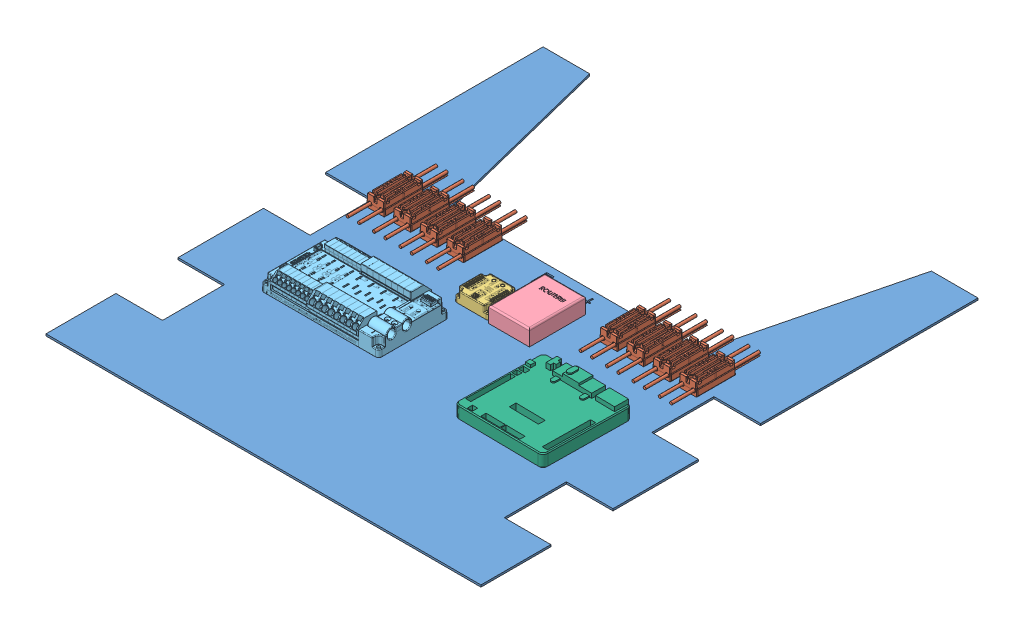
SolidWorks assembly 2017 electronics plate, configuration Default. Lengths in mm.
Overall size (711.2 41.27 812.8).
13 component instances, 6 part files, 6 mates.
Components (placement in the parent):
- electronics plate-1: electronics plate [Default] at origin size (711.2 3.17 812.8)
- Victor-SP-Motor-controller-20217-9090-1: Victor-SP-Motor-controller-20217-9090 [Default] at (-258.5801 9.1448 -219.6738) size (30.24 20.93 144.78)
- Victor-SP-Motor-controller-20217-9090-3: Victor-SP-Motor-controller-20217-9090 [Default] at (-215.4001 9.1448 -219.6738) size (30.24 20.93 144.78)
- Victor-SP-Motor-controller-20217-9090-4: Victor-SP-Motor-controller-20217-9090 [Default] at (-172.2201 9.1448 -219.6738) size (30.24 20.93 144.78)
- Victor-SP-Motor-controller-20217-9090-5: Victor-SP-Motor-controller-20217-9090 [Default] at (-129.0401 9.1448 -219.6738) size (30.24 20.93 144.78)
- VoltReg-217-4245-1: VoltReg-217-4245 [Default] at (-39.4381 10.281 -153.6848) size (56.39 19.92 51.56)
- RouterCrude-1: RouterCrude [Default] at (37.6355 15.875 -155.8516) size (66.67 25.4 92.08)
- PowerDistribution-1: PowerDistribution [Default] at (-149.0064 9.8552 -39.9983) x (-1 0 0) z (0 0 -1) size (192.68 36.15 120.93)
- Victor-SP-Motor-controller-20217-9090-9: Victor-SP-Motor-controller-20217-9090 [Default] at (122.4199 9.1448 -219.6738) size (30.24 20.93 144.78)
- Victor-SP-Motor-controller-20217-9090-10: Victor-SP-Motor-controller-20217-9090 [Default] at (165.5999 9.1448 -219.6738) size (30.24 20.93 144.78)
- Victor-SP-Motor-controller-20217-9090-11: Victor-SP-Motor-controller-20217-9090 [Default] at (208.7799 9.1448 -219.6738) size (30.24 20.93 144.78)
- Victor-SP-Motor-controller-20217-9090-12: Victor-SP-Motor-controller-20217-9090 [Default] at (251.9599 9.1448 -219.6738) size (30.24 20.93 144.78)
- RoboRIO-1: RoboRIO [Default] at (170.9718 13.675 -32.4938) x (0.999904 0 0.013829) z (-0.013829 0 0.999904) size (147 34 144)
Mates (geometry in assembly coordinates):
- Coincident2: coordinate: point of electronics plate-1; point of assembly
- Coincident3: coincident anti-aligned: plane of electronics plate-1 through (0 3.175 0) normal (0 1 0); plane of Victor-SP-Motor-controller-20217-9090-1 through (-258.5801 3.175 -219.6738) normal (0 -1 0)
- Coincident4: coincident anti-aligned: plane of electronics plate-1 through (0 3.175 0) normal (0 1 0); plane of VoltReg-217-4245-1 through (-16.0938 3.175 -173.232) normal (0 -1 0)
- Coincident5: coincident anti-aligned: plane of electronics plate-1 through (0 3.175 0) normal (0 1 0); plane of PowerDistribution-1 through (-241.0306 3.175 -97.4023) normal (0 -1 0)
- Parallel1: parallel anti-aligned: line of electronics plate-1 through (203.2 3.175 -254) axis (-1 0 0); line of PowerDistribution-1 through (-231.2471 3.4334 -97.3978) axis (1 0 0)
- Coincident7: coincident anti-aligned: plane of electronics plate-1 through (0 3.175 0) normal (0 1 0); plane of RoboRIO-1 through (170.9718 3.175 -32.4938) normal (0 -1 0)
